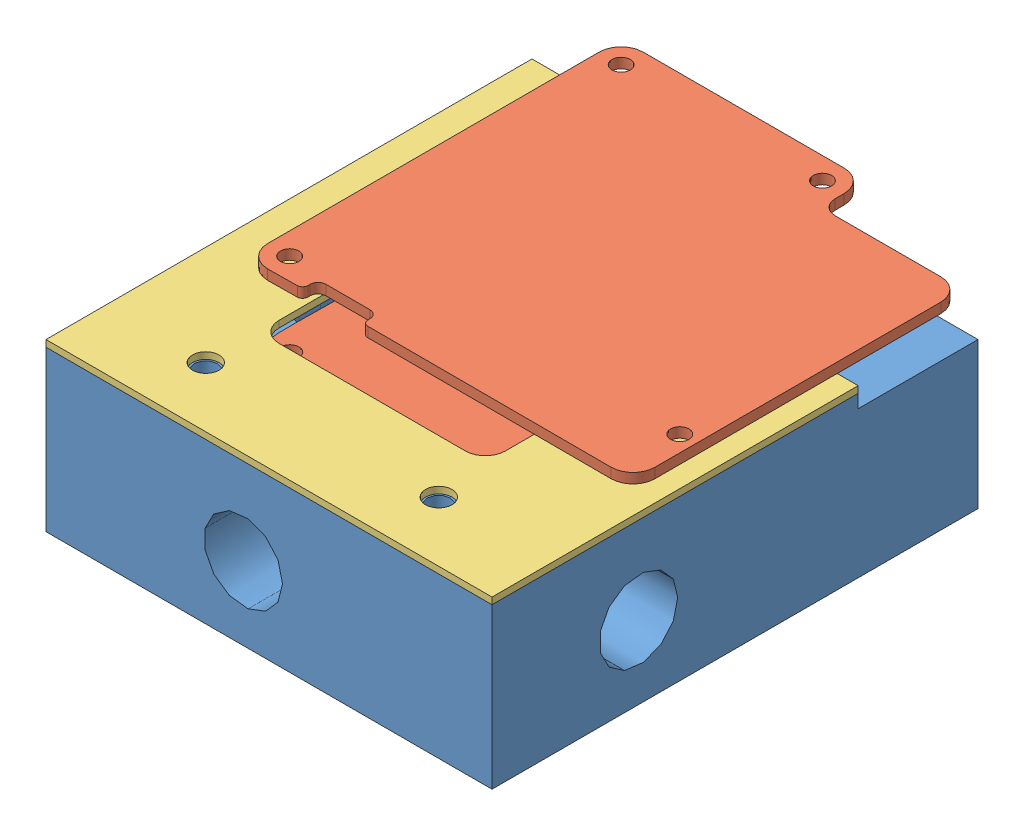
SolidWorks assembly SCK1.5Assembly, configuration Default. Lengths in mm.
Overall size (73.35 36 73).
3 component instances, 3 part files, 6 mates.
Components (placement in the parent):
- BaseSCK1.5-1: BaseSCK1.5 [Default] at origin size (67 24 73)
- SCK1.5MiCS-1: SCK1.5MiCS [Default] at (73.8822 20.007 -14.5351) x (-1 0 0.000148) z (-0.000148 0 -1) size (58.4 15.1 56.64)
- SCKClip1.5-1: SCKClip1.5 [Default] at (52 20.5 -15) size (67 1 73)
Mates (geometry in assembly coordinates):
- Coincident1: coincident anti-aligned: plane of BaseSCK1.5-1 through (20 18.5 -27) normal (0 1 0); plane of SCK1.5MiCS-1 through (15.1644 18.5 -25.3995) normal (0 -1 0)
- Concentric1: concentric anti-aligned: circle of BaseSCK1.5-1; circle of SCK1.5MiCS-1
- Concentric2: concentric anti-aligned: circle of BaseSCK1.5-1; circle of SCK1.5MiCS-1
- Coincident2: coincident anti-aligned: plane of BaseSCK1.5-1 through (0 20.5 0) normal (0 1 0); plane of SCKClip1.5-1 through (46 20.5 -20) normal (0 -1 0)
- Coincident3: coincident aligned: plane of BaseSCK1.5-1 through (67 15 0) normal (1 0 0); plane of SCKClip1.5-1 through (67 21.5 -15) normal (1 0 0)
- Coincident4: coincident aligned: plane of BaseSCK1.5-1 through (0 15 0) normal (0 0 1); plane of SCKClip1.5-1 through (67 21.5 0) normal (0 0 1)
